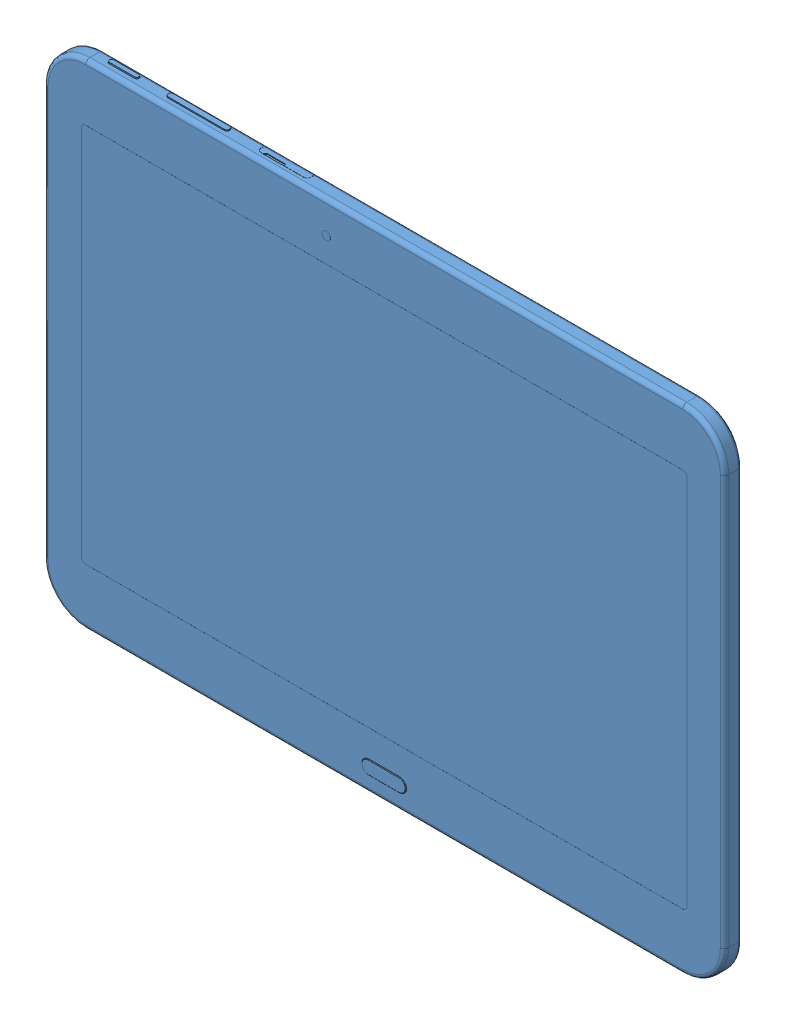
SolidWorks assembly RK3568_TABLET_10.1, configuration Default. Lengths in mm.
Overall size (243.77 176.9 8.8).
4 component instances, 2 part files, 0 mates.
Components (placement in the parent):
- TABLET_10.1.STEP-1: TABLET_10.1.STEP [Default] at origin size (243.77 176.9 8.8)
  - Samsun-Galaxy-Tab-4-10.1-SM-T530.STEP.STEP-1: Samsun-Galaxy-Tab-4-10.1-SM-T530.STEP.STEP [Default] at origin size (243.77 176.9 8.8)
    - Body.STEP.STEP-1: Body.STEP.STEP [Default] at (-83.3861 10.9425 0) size (243.77 176.9 8.8)
    - micro_usb.STEP.STEP-1: micro_usb.STEP.STEP [Default] at (-83.3861 -73.4575 -0.175) x (-1 0 0) z (0 -1 0) size (7.82 2.72 5.01)
